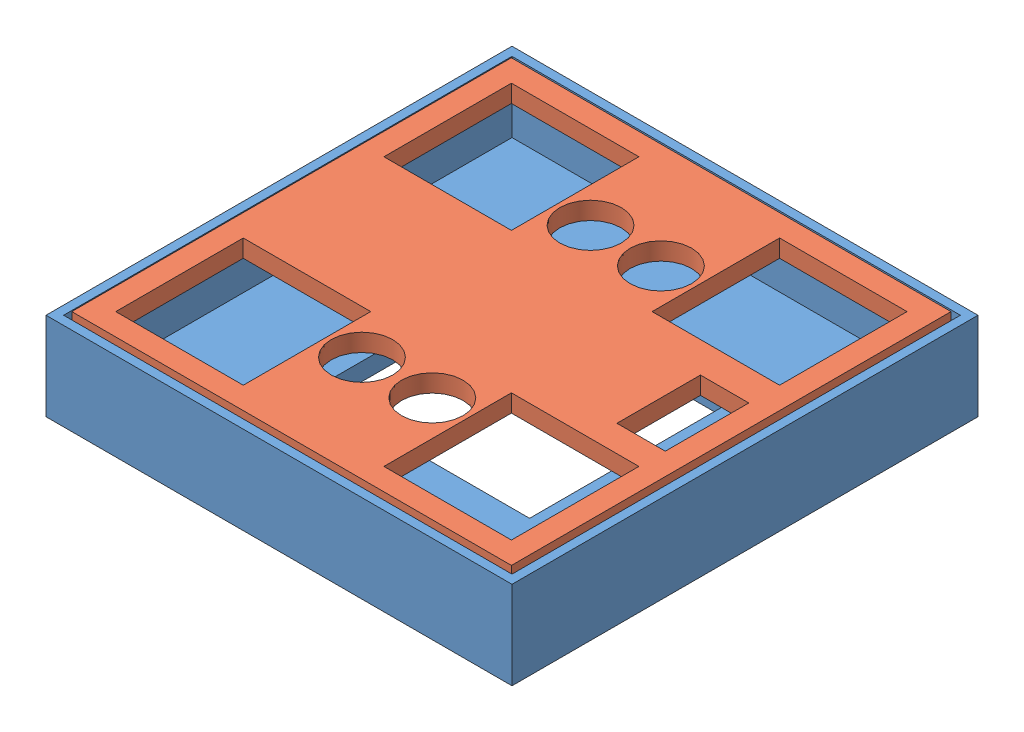
SolidWorks assembly assembly, configuration Default. Lengths in mm.
Overall size (53 10.32 53).
2 component instances, 2 part files, 1 mates.
Components (placement in the parent):
- Backplate-1: Backplate [Default] at (-3.8811 10.7196 99.9568) size (53 10 53)
- TopPlate-2: TopPlate [Default] at (-2.4498 19.0428 98.455) size (50 2 50)
Mates (geometry in assembly coordinates):
- Lock2: lock: unknown of Backplate-1; unknown of TopPlate-2
